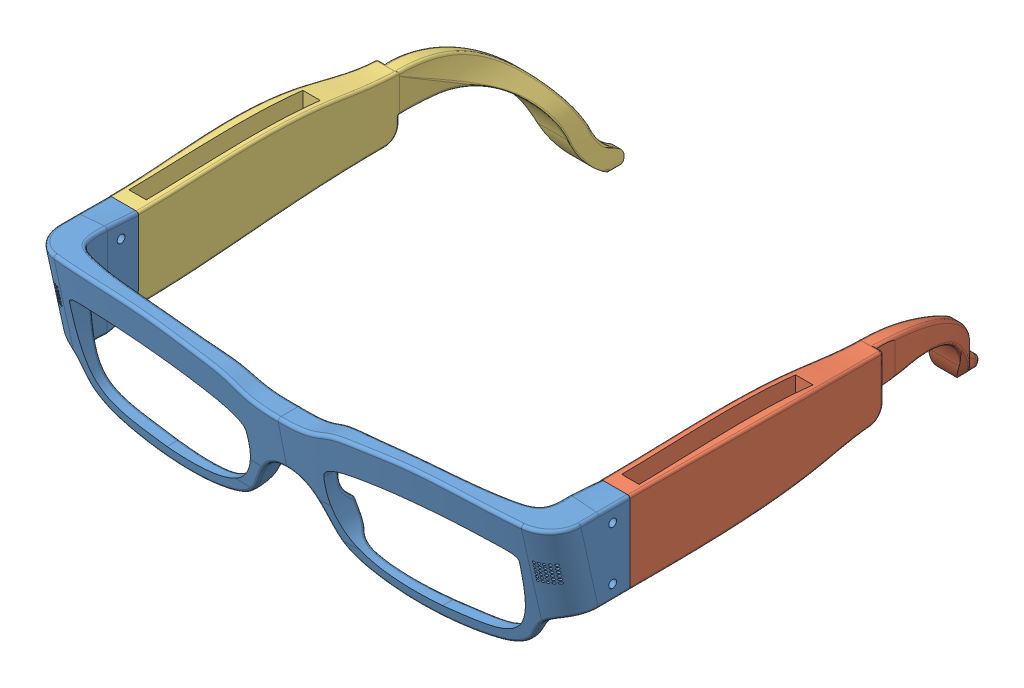
SolidWorks assembly allglass, configuration 默认. Lengths in mm.
Overall size (187.03 60.41 184.15).
3 component instances, 3 part files, 6 mates.
Components (placement in the parent):
- GlassesFRAME-1: GlassesFRAME [Default] at (-2.8966 181.2742 -22.3963) size (181.04 60.41 36.94)
- GlassesLEG-1: GlassesLEG [Default] at (76.9002 196.9521 -33.1297) x (0 0 1) z (-1 0 0) size (163.21 53.56 35.28)
- GlassesLEG_Mirror-1: GlassesLEG_Mirror [Default] at (17.3065 196.9521 -33.1297) x (0 0 1) z (-1 0 0) size (163.21 53.56 127.44)
Mates (geometry in assembly coordinates):
- Concentric2: concentric aligned: circle of GlassesFRAME-1; circle of GlassesLEG_Mirror-1
- Width1: width anti-aligned: plane of GlassesFRAME-1 through (-85.2648 205.2893 -16.1297) normal (-1 0 0); plane of GlassesFRAME-1 through (-90.2648 198.9521 -16.1297) normal (1 0 0); plane of GlassesLEG_Mirror-1 through (-85.2648 205.2893 -17.1297) normal (1 0 0); plane of GlassesLEG_Mirror-1 through (-90.2648 205.2893 -17.1297) normal (-1 0 0)
- Parallel1: parallel anti-aligned: plane of GlassesFRAME-1 through (-92.7648 225.1882 -33.1297) normal (0 0 -1); plane of GlassesLEG_Mirror-1 through (-82.6935 196.9521 -33.1297) normal (0 0 1)
- Concentric3: concentric aligned: circle of GlassesFRAME-1; circle of GlassesLEG-1
- Width2: width anti-aligned: plane of GlassesFRAME-1 through (84.4715 198.9521 -16.1297) normal (-1 0 0); plane of GlassesFRAME-1 through (79.4715 205.2893 -16.1297) normal (1 0 0); plane of GlassesLEG-1 through (84.4715 205.2893 -17.1297) normal (1 0 0); plane of GlassesLEG-1 through (79.4715 205.2893 -17.1297) normal (-1 0 0)
- Coincident4: coincident anti-aligned: plane of GlassesFRAME-1 through (86.9715 225.1882 -33.1297) normal (0 0 -1); plane of GlassesLEG-1 through (76.9002 196.9521 -33.1297) normal (0 0 1)
